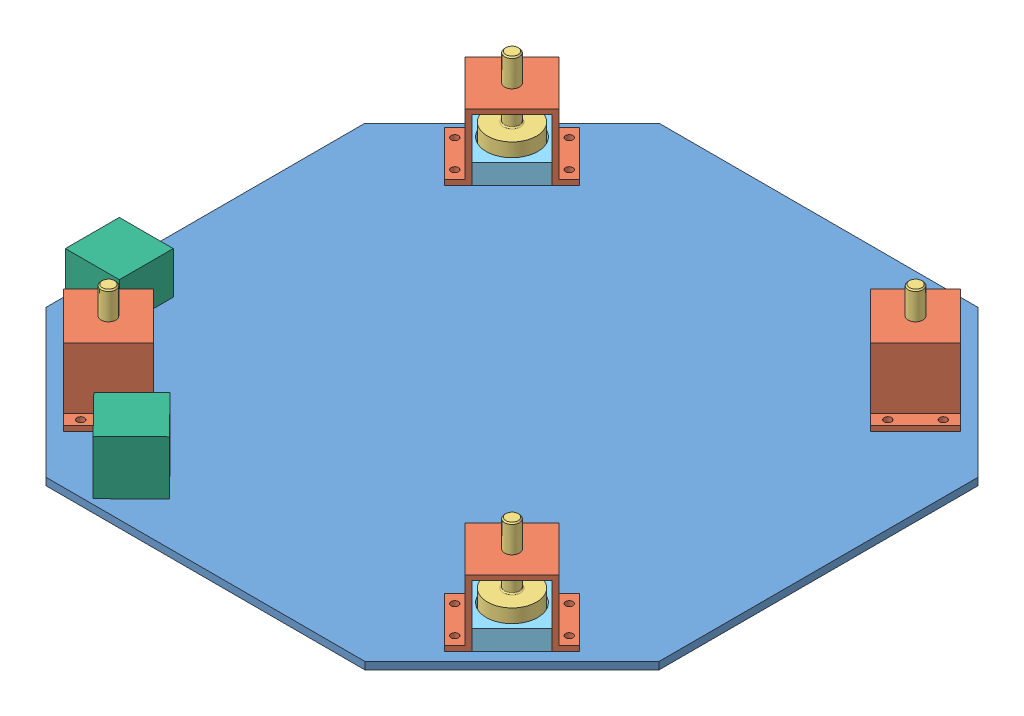
SolidWorks assembly Base roulante, configuration Défaut. Lengths in mm.
Overall size (335.11 47.17 327.58).
27 component instances, 6 part files, 5 mates.
Components (placement in the parent):
- fond_hexagonal-1: fond_hexagonal [Défaut] at (-9.7002 -3.9691 0) size (335.11 3 327.58)
- fixation bille-1: fixation bille [Défaut] at (-94.7689 7.0282 -97.8602) x (0.707107 0 -0.707107) z (0.707107 0 0.707107) size (39 47.17 26)
  - Fixation bille-1: Fixation bille [Défaut] at (-20.545 -7.9974 0) size (39 27 26)
  - Roulette à bille 687-679-1: Roulette à bille 687-679 [Default] at (-3.7752 -6.3161 13.5736) x (0.301673 0 0.953411) z (-0.953411 0 0.301673) size (20 47.17 20)
    - Roulette D20-1: Roulette D20 [Default] at (-2.1367 -5.4811 4.8512) size (20 42 20)
    - bille D12_5-1: bille D12_5 [Default] at (-2.1367 -2.2311 4.8512) x (0.951271 -0.300034 -0.071154) z (0.043636 -0.097448 0.994284) size (12.5 12.5 12.5)
  - Guide_roulette-1: Guide_roulette [Défaut] at (2.455 -7.9974 0) x (-1 0 0) z (0 0 -1) size (23 8 26)
- fixation bille-2: fixation bille [Défaut] at (-107.5604 7.0282 85.0687) x (-0.707107 0 -0.707107) z (0.707107 0 -0.707107) size (39 47.17 26)
  - Fixation bille-1: Fixation bille [Défaut] at (-20.545 -7.9974 0) size (39 27 26)
  - Roulette à bille 687-679-1: Roulette à bille 687-679 [Default] at (-3.7752 -6.3161 13.5736) x (0.301673 0 0.953411) z (-0.953411 0 0.301673) size (20 47.17 20)
    - Roulette D20-1: Roulette D20 [Default] at (-2.1367 -5.4811 4.8512) size (20 42 20)
    - bille D12_5-1: bille D12_5 [Default] at (-2.1367 -2.2311 4.8512) x (0.951271 -0.300034 -0.071154) z (0.043636 -0.097448 0.994284) size (12.5 12.5 12.5)
  - Guide_roulette-1: Guide_roulette [Défaut] at (2.455 -7.9974 0) x (-1 0 0) z (0 0 -1) size (23 8 26)
- fixation bille-3: fixation bille [Défaut] at (75.3685 7.0282 97.8602) x (-0.707107 0 0.707107) z (-0.707107 0 -0.707107) size (39 47.17 26)
  - Fixation bille-1: Fixation bille [Défaut] at (-20.545 -7.9974 0) size (39 27 26)
  - Roulette à bille 687-679-1: Roulette à bille 687-679 [Default] at (-3.7752 -6.3161 13.5736) x (0.301673 0 0.953411) z (-0.953411 0 0.301673) size (20 47.17 20)
    - Roulette D20-1: Roulette D20 [Default] at (-2.1367 -5.4811 4.8512) size (20 42 20)
    - bille D12_5-1: bille D12_5 [Default] at (-2.1367 -2.2311 4.8512) x (0.951271 -0.300034 -0.071154) z (0.043636 -0.097448 0.994284) size (12.5 12.5 12.5)
  - Guide_roulette-1: Guide_roulette [Défaut] at (2.455 -7.9974 0) x (-1 0 0) z (0 0 -1) size (23 8 26)
- fixation bille-4: fixation bille [Défaut] at (88.1601 7.0282 -85.0687) x (0.707107 0 0.707107) z (-0.707107 0 0.707107) size (39 47.17 26)
  - Fixation bille-1: Fixation bille [Défaut] at (-20.545 -7.9974 0) size (39 27 26)
  - Roulette à bille 687-679-1: Roulette à bille 687-679 [Default] at (-3.7752 -6.3161 13.5736) x (0.301673 0 0.953411) z (-0.953411 0 0.301673) size (20 47.17 20)
    - Roulette D20-1: Roulette D20 [Default] at (-2.1367 -5.4811 4.8512) size (20 42 20)
    - bille D12_5-1: bille D12_5 [Default] at (-2.1367 -2.2311 4.8512) x (0.951271 -0.300034 -0.071154) z (0.043636 -0.097448 0.994284) size (12.5 12.5 12.5)
  - Guide_roulette-1: Guide_roulette [Défaut] at (2.455 -7.9974 0) x (-1 0 0) z (0 0 -1) size (23 8 26)
- simu_profilé-1: simu_profilé [Défaut] at (-134.3378 -5.7888 57.4746) size (22 22 22)
- simu_profilé-2: simu_profilé [Défaut] at (-57.2644 -0.9691 91.8378) x (0.700491 0 0.713661) z (0 -1 0) size (22 22 22)
Mates (geometry in assembly coordinates):
- Coïncidente1: coincident anti-aligned: plane of fond_hexagonal-1 through (-134.7002 -0.9691 -125) normal (0 1 0); plane of fixation bille-1/Fixation bille-1 through (-96.5684 -0.9691 -59.2911) normal (0 -1 0)
- Distance2: distance = 5 mm: line of fond_hexagonal-1; line of fixation bille-1/Fixation bille-1
- Coïncidente12: coincident anti-aligned: unknown of fixation bille-1/Fixation bille-1
- Coïncidente13: coincident anti-aligned: unknown of simu_profilé-2; unknown of fond_hexagonal-1
- PLAN1: unknown: moEndPointRef_w of fond_hexagonal-1; unknown of fond_hexagonal-1
